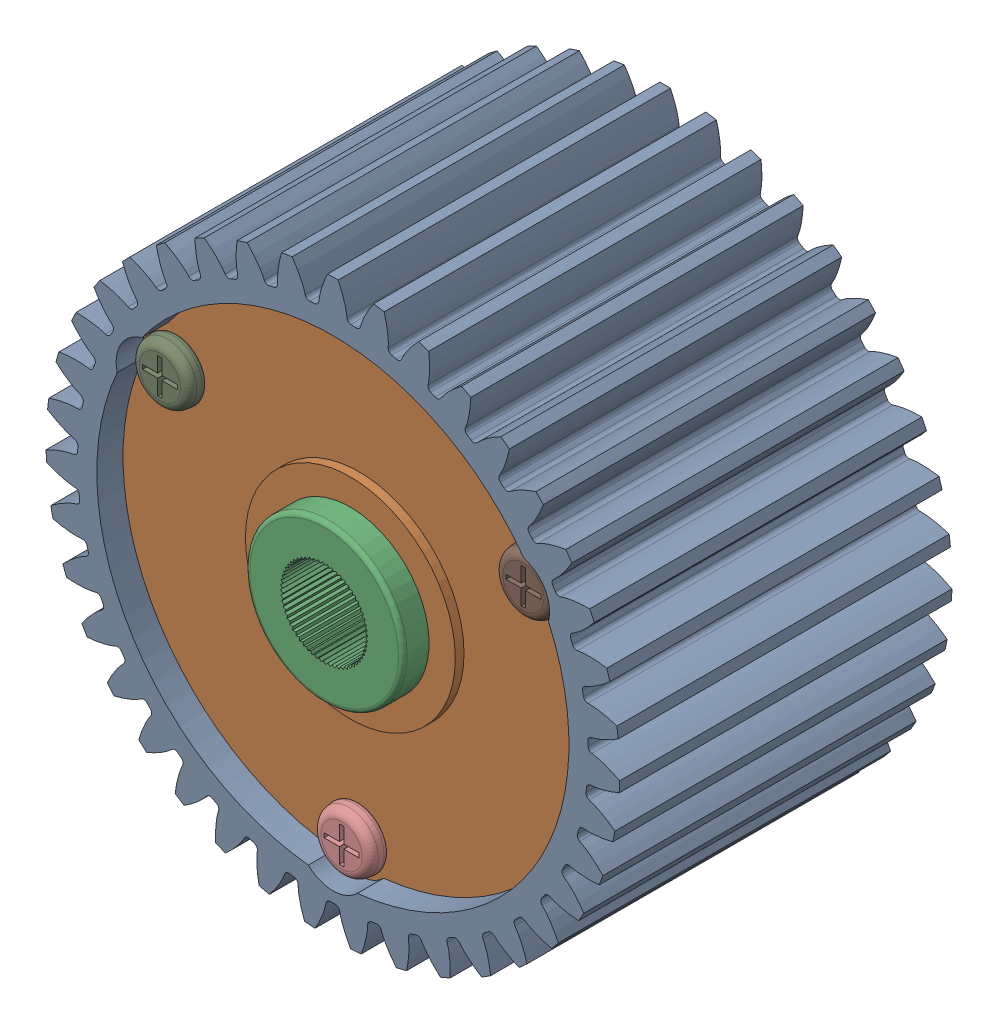
SolidWorks assembly Differentiel, configuration Défaut. Lengths in mm.
Overall size (37.32 37.13 21).
11 component instances, 6 part files, 22 mates.
Components (placement in the parent):
- Couronne de différentiel-1: Couronne de différentiel [Configuration] at origin size (32.79 32.77 19)
- Différentiel-G3-1: Différentiel-G3 [Défaut] at (0 0 18.5) x (-0.5 0.866025 0) z (0 0 -1) size (27 27.5 7.5)
- Différentiel-MA16-1: Différentiel-MA16 [Configuration] at (0 0 16) x (0.46901 0.883193 0) z (0 0 -1) size (17.57 17.54 7.5)
- Différentiel-MA16-2: Différentiel-MA16 [Configuration] at (0 0 4) size (17.57 17.54 7.5)
- Différentiel-MA18-1: Différentiel-MA18 [Défaut] at (0 0 10) x (1 0 0) z (0 1 0) size (22.9 6 19.83)
- Différentiel-MA17-1: Différentiel-MA17 [Configuration] at (-8.0107 -4.625 10) x (0.489624 -0.848054 0.202661) z (0.866025 0.5 0) size (11 11 5.25)
- Différentiel-MA17-2: Différentiel-MA17 [Configuration] at (8.0107 -4.625 10) x (0.162457 0.281385 0.945743) z (-0.866025 0.5 0) size (11 11 5.25)
- Différentiel-MA17-3: Différentiel-MA17 [Configuration] at (0 9.25 10) x (-0.304094 0 -0.952642) z (0 -1 0) size (11 11 5.25)
- Vis-M2-8-1: Vis-M2-8 [Défaut] at (-10.3923 6 18.5) size (3.42 3.42 9)
- Vis-M2-8-2: Vis-M2-8 [Défaut] at (0 -12 18.5) size (3.42 3.42 9)
- Vis-M2-8-3: Vis-M2-8 [Défaut] at (10.3923 6 18.5) size (3.42 3.42 9)
Mates (geometry in assembly coordinates):
- Coïncidente1: coincident anti-aligned: plane of Couronne de différentiel-1 through (-10.3923 6 17) normal (0 0 1); plane of Différentiel-G3-1 through (-5.1962 3 17) normal (0 0 -1)
- Coïncidente2: coincident anti-aligned: axis of Couronne de différentiel-1 through (-10.3923 6 20) axis (0 0 -1); axis of Différentiel-G3-1 through (-10.3923 6 17) axis (0 0 1)
- Coïncidente3: coincident aligned: axis of Couronne de différentiel-1 through (0 0 3) axis (0 0 1); axis of Différentiel-G3-1 through (0 0 17) axis (0 0 1)
- Coïncidente4: coincident anti-aligned: plane of Couronne de différentiel-1 through (0 0 3) normal (0 0 1); plane of Différentiel-MA16-2 through (0 0 3) normal (0 0 -1)
- Coïncidente5: coincident aligned: axis of Couronne de différentiel-1 through (0 0 3) axis (0 0 1); axis of Différentiel-MA16-2 through (0 0 -0.25) axis (0 0 1)
- Coïncidente6: coincident anti-aligned: axis of Différentiel-G3-1 through (0 0 17) axis (0 0 1); axis of Différentiel-MA16-1 through (0 0 15.1566) axis (0 0 -1)
- Coïncidente7: coincident anti-aligned: plane of Différentiel-G3-1 through (-5.1962 3 17) normal (0 0 -1); plane of Différentiel-MA16-1 through (0 0 17) normal (0 0 1)
- Coïncidente8: coincident aligned: axis of Différentiel-MA18-1 through (0 12.5 10) axis (0 -1 0); axis of Différentiel-MA17-3 through (0 8.75 10) axis (0 -1 0)
- A distance1: distance = 3 mm aligned: plane of Différentiel-MA18-1 through (0 12.5 10) normal (0 1 0); plane of Différentiel-MA17-3 through (0 9.5 10) normal (0 1 0)
- Coïncidente9: coincident aligned: axis of Différentiel-MA18-1 through (-10.8253 -6.25 10) axis (0.866025 0.5 0); axis of Différentiel-MA17-1 through (-7.5777 -4.375 10) axis (0.866025 0.5 0)
- A distance2: distance = 3 mm aligned: plane of Différentiel-MA18-1 through (-10.8253 -6.25 10) normal (-0.866025 -0.5 0); plane of Différentiel-MA17-1
- Coïncidente10: coincident aligned: axis of Différentiel-MA18-1 through (10.8253 -6.25 10) axis (-0.866025 0.5 0); axis of Différentiel-MA17-2 through (7.5777 -4.375 10) axis (-0.866025 0.5 0)
- A distance3: distance = 3 mm aligned: plane of Différentiel-MA18-1 through (10.8253 -6.25 10) normal (0.866025 -0.5 0); plane of Différentiel-MA17-2
- Coïncidente11: coincident anti-aligned: axis of Couronne de différentiel-1 through (0 0 3) axis (0 0 1); axis of Différentiel-MA18-1 through (0 0 13) axis (0 0 -1)
- A distance4: distance = 2 mm: plane of Couronne de différentiel-1 through (1.25 13 8) normal (0 0 1); axis of Différentiel-MA18-1 through (0 12.5 10) axis (0 -1 0)
- Parallèle1: parallel: plane of Couronne de différentiel-1 through (-10.6333 -7.5825 8) normal (-0.5 0.866025 0); axis of Différentiel-MA18-1 through (-10.8253 -6.25 10) axis (0.866025 0.5 0)
- Coïncidente12: coincident aligned: axis of Différentiel-G3-1 through (-10.3923 6 17) axis (0 0 1); axis of Vis-M2-8-1 through (-10.3923 6 10.75) axis (0 0 1)
- Coïncidente13: coincident anti-aligned: plane of Différentiel-G3-1 through (-5.1962 3 18.5) normal (0 0 1); plane of Vis-M2-8-1 through (-10.3923 6 18.5) normal (0 0 -1)
- Coïncidente14: coincident aligned: axis of Différentiel-G3-1 through (10.3923 6 17) axis (0 0 1); axis of Vis-M2-8-3 through (10.3923 6 10.75) axis (0 0 1)
- Coïncidente15: coincident anti-aligned: plane of Différentiel-G3-1 through (-5.1962 3 18.5) normal (0 0 1); plane of Vis-M2-8-3 through (10.3923 6 18.5) normal (0 0 -1)
- Coïncidente16: coincident aligned: axis of Différentiel-G3-1 through (0 -12 17) axis (0 0 1); axis of Vis-M2-8-2 through (0 -12 10.75) axis (0 0 1)
- Coïncidente17: coincident anti-aligned: plane of Différentiel-G3-1 through (-5.1962 3 18.5) normal (0 0 1); plane of Vis-M2-8-2 through (0 -12 18.5) normal (0 0 -1)
